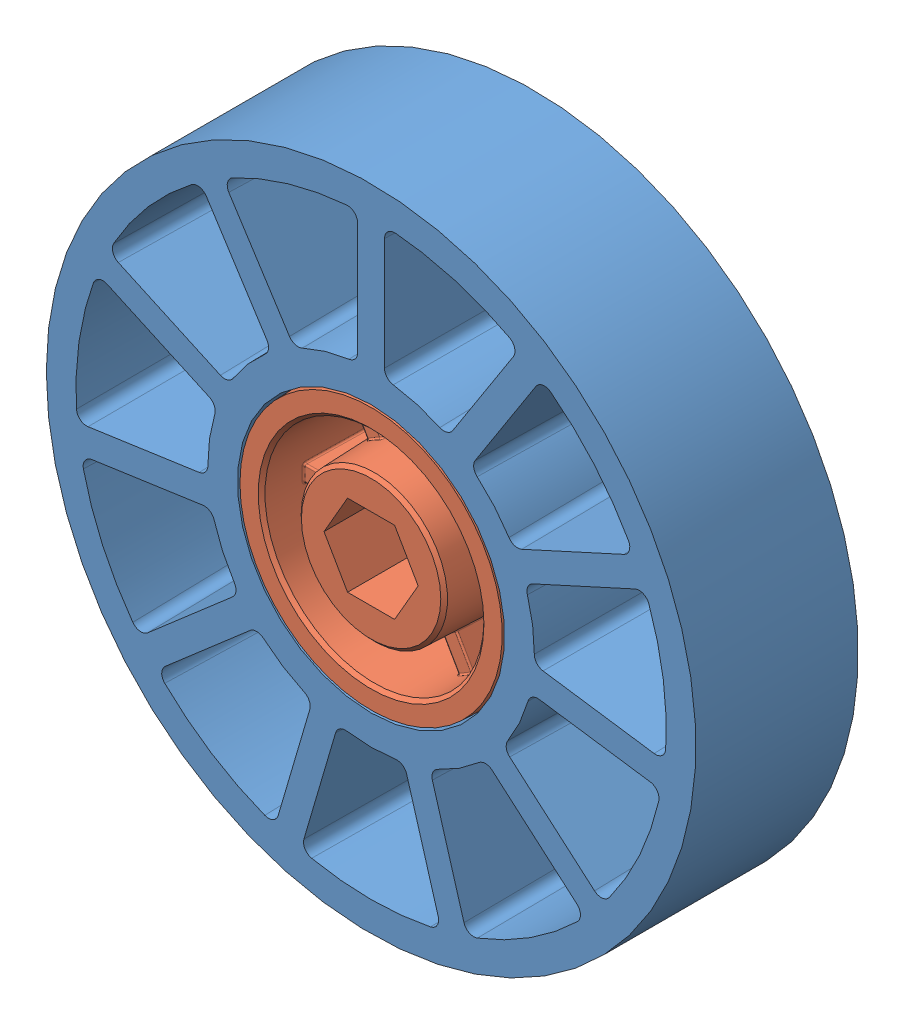
SolidWorks assembly 4inCompliantWheel, configuration Default. Lengths in mm.
Overall size (101.6 101.6 25.74).
2 component instances, 2 part files, 0 mates.
Components (placement in the parent):
- 4IN Compliant Wheel FINAL Overmold-1: 4IN Compliant Wheel FINAL Overmold [Default] at (-16.2374 3.8509 18.652) size (101.6 101.6 25.74)
- 2in Wheel Intergrated 0500 HEX Hub-1: 2in Wheel Intergrated 0500 HEX Hub [Default] at (-16.2374 3.8509 5.952) x (-1 0 0) z (0 0 -1) size (41.91 41.91 25.4)
